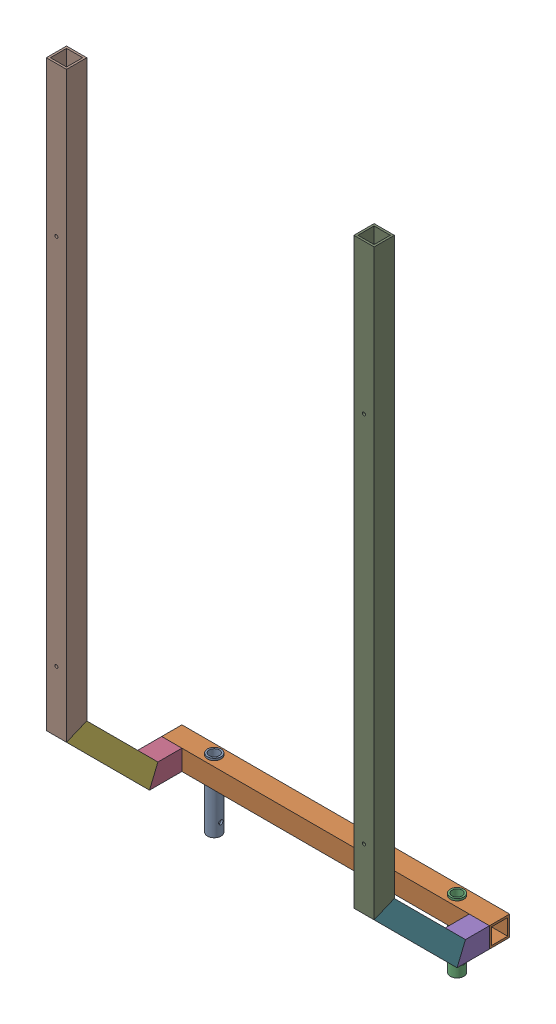
SolidWorks assembly GE-16008_ASM, configuration Default. Lengths in mm.
Overall size (514.35 1117.64 212.76).
9 component instances, 9 part files, 0 mates.
Components (placement in the parent):
- GE-16008-01_AF0-1: GE-16008-01_AF0 [Default] at origin size (21.34 107.95 21.34)
- GE-16008-02_AF0-1: GE-16008-02_AF0 [Default] at (-66.675 104.775 15.875) size (514.35 31.75 31.75)
- GE-16008-01_AF1-1: GE-16008-01_AF1 [Default] at (381 0 0) size (21.34 107.95 21.34)
- GE-16008-04_AF0-1: GE-16008-04_AF0 [Default] at (-34.925 73.025 66.675) x (-1 0 0) z (0 0 -1) size (31.75 31.75 50.8)
- GE-16008-04_AF1-1: GE-16008-04_AF1 [Default] at (447.675 73.025 66.675) x (-1 0 0) z (0 0 -1) size (31.75 31.75 50.8)
- GE-16008-03_AF0-1: GE-16008-03_AF0 [Default] at (-34.925 203.2387 196.8887) x (-1 0 0) z (0 -0.707107 0.707107) size (31.75 184.15 31.75)
- GE-16008-03_AF1-1: GE-16008-03_AF1 [Default] at (415.925 73.025 66.675) x (1 0 0) z (0 -0.707107 0.707107) size (31.75 184.15 31.75)
- GE-16008-05_AF0-1: GE-16008-05_AF0 [Default] at (-34.925 1117.6387 196.8887) x (-1 0 0) z (0 0 1) size (31.75 914.4 31.75)
- GE-16008-05_AF1-1: GE-16008-05_AF1 [Default] at (447.675 1117.6387 196.8887) x (-1 0 0) z (0 0 1) size (31.75 914.4 31.75)
